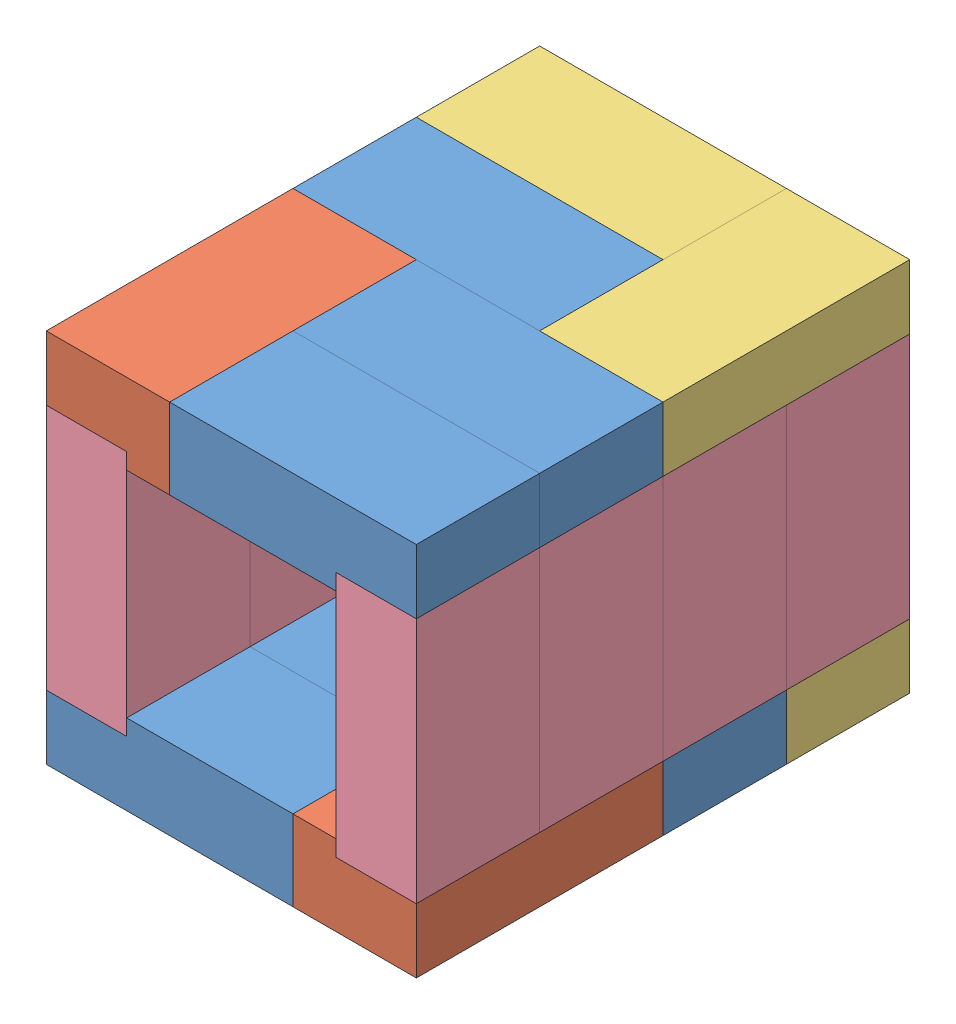
SolidWorks assembly Assem1, configuration Default. Lengths in mm.
Overall size (353.06 350 465.32).
27 component instances, 5 part files, 11 mates.
Components (placement in the parent):
- Heat Treat Asm Top-Bot Alt Long-1: Heat Treat Asm Top-Bot Alt Long [Default] at (93.1186 153.6522 453.2582) size (345 75 460)
  - Brick-Sharp-BackCut-1: Brick-Sharp-BackCut [Default] at (102.0414 124.8114 164.7515) size (230 75 115)
  - Brick-Sharp-SideCut-1: Brick-Sharp-SideCut [Default] at (274.5414 124.8114 107.2515) x (0 0 1) z (-1 0 0) size (230 75 115)
  - Brick-Sharp-BackCut-2: Brick-Sharp-BackCut [Default] at (102.0414 124.8114 49.7515) size (230 75 115)
  - Brick-Sharp-BackCut-3: Brick-Sharp-BackCut [Default] at (217.0414 124.8114 -65.2485) x (-1 0 0) z (0 0 -1) size (230 75 115)
  - Brick-Sharp-BackLeftCut-2: Brick-Sharp-BackLeftCut [Default] at (217.0414 124.8114 -180.2485) x (-1 0 0) z (0 0 -1) size (230 75 115)
  - Brick-Sharp-BackLeftCut-3: Brick-Sharp-BackLeftCut [Default] at (44.5414 124.8114 -122.7485) x (0 0 1) z (-1 0 0) size (230 75 115)
- Heat Treat Asm Top-Bot Alt Long-2: Heat Treat Asm Top-Bot Alt Long [Default] at (412.2014 678.275 453.2582) x (-1 0 0) z (0 0 1) size (345 75 460)
  - Brick-Sharp-BackCut-1: Brick-Sharp-BackCut [Default] at (102.0414 124.8114 164.7515) size (230 75 115)
  - Brick-Sharp-SideCut-1: Brick-Sharp-SideCut [Default] at (274.5414 124.8114 107.2515) x (0 0 1) z (-1 0 0) size (230 75 115)
  - Brick-Sharp-BackCut-2: Brick-Sharp-BackCut [Default] at (102.0414 124.8114 49.7515) size (230 75 115)
  - Brick-Sharp-BackCut-3: Brick-Sharp-BackCut [Default] at (217.0414 124.8114 -65.2485) x (-1 0 0) z (0 0 -1) size (230 75 115)
  - Brick-Sharp-BackLeftCut-2: Brick-Sharp-BackLeftCut [Default] at (217.0414 124.8114 -180.2485) x (-1 0 0) z (0 0 -1) size (230 75 115)
  - Brick-Sharp-BackLeftCut-3: Brick-Sharp-BackLeftCut [Default] at (44.5414 124.8114 -122.7485) x (0 0 1) z (-1 0 0) size (230 75 115)
- Heat Treat Asm Back-1: Heat Treat Asm Back [Default] at (559.1645 290.8305 184.2616) x (-0.008726 0.008727 0.999924) z (-0.999962 0 -0.008727) size (462.63 234.01 79.01)
  - Brick-Sharp-1: Brick-Sharp [Default] at (91.3299 124.3408 170.7235) x (-0.008727 -0.999962 0) z (-0.999924 0.008726 0.008727) size (230 75 115)
  - Brick-Sharp-2: Brick-Sharp [Default] at (206.3211 123.3373 169.7199) x (0.008727 0.999962 0) z (-0.999924 0.008726 0.008727) size (230 75 115)
  - Brick-Sharp-3: Brick-Sharp [Default] at (436.3036 121.3303 167.7128) x (-0.008727 -0.999962 0) z (0.999924 -0.008726 -0.008727) size (230 75 115)
  - Brick-Sharp-4: Brick-Sharp [Default] at (321.3124 122.3338 168.7164) x (-0.008727 -0.999962 0) z (0.999924 -0.008726 -0.008727) size (230 75 115)
- Heat Treat Asm Back-2: Heat Treat Asm Back [Default] at (-53.8445 290.8305 706.7578) x (0.008726 0.008727 -0.999924) z (0.999962 0 0.008727) size (462.63 234.01 79.01)
  - Brick-Sharp-1: Brick-Sharp [Default] at (91.3299 124.3408 170.7235) x (-0.008727 -0.999962 0) z (-0.999924 0.008726 0.008727) size (230 75 115)
  - Brick-Sharp-2: Brick-Sharp [Default] at (206.3211 123.3373 169.7199) x (0.008727 0.999962 0) z (-0.999924 0.008726 0.008727) size (230 75 115)
  - Brick-Sharp-3: Brick-Sharp [Default] at (436.3036 121.3303 167.7128) x (-0.008727 -0.999962 0) z (0.999924 -0.008726 -0.008727) size (230 75 115)
  - Brick-Sharp-4: Brick-Sharp [Default] at (321.3124 122.3338 168.7164) x (-0.008727 -0.999962 0) z (0.999924 -0.008726 -0.008727) size (230 75 115)
- Heat Treat Asm Back Alt-1: Heat Treat Asm Back Alt [Default] at (386.4278 496.0717 124.4337) x (0 -1 0) z (-1 0 0) size (230 75 195)
  - Brick-Sharp-1: Brick-Sharp [Default] at (80.1081 128.5759 173.7678) size (230 75 115)
  - Brick-Sharp-Trimmed-1: Brick-Sharp-Trimmed [Default] at (80.1081 128.5759 58.7678) size (230 75 80)
Mates (geometry in assembly coordinates):
- Coincident1: coincident anti-aligned: line of Heat Treat Asm Top-Bot Alt Long-1/Brick-Sharp-SideCut-1 through (350.16 300.9636 675.5097) axis (1 0 0); line of Heat Treat Asm Back-1/Brick-Sharp-3 through (425.16 300.9636 675.5097) axis (-1 0 0)
- Coincident2: coincident anti-aligned: line of Heat Treat Asm Top-Bot Alt Long-1/Brick-Sharp-BackLeftCut-2 through (425.16 300.9636 330.5097) axis (0 0 -1); line of Heat Treat Asm Back-1/Brick-Sharp-1 through (425.16 300.9636 215.5097) axis (0 0 1)
- Coincident4: coincident: plane of Heat Treat Asm Top-Bot Alt Long-1/Brick-Sharp-BackCut-1 through (195.16 300.9636 618.0097) normal (0 1 0); plane of Heat Treat Asm Back-2/Brick-Sharp-1 through (155.16 300.9636 560.5097) normal (0 -1 0)
- Coincident5: coincident: line of Heat Treat Asm Top-Bot Alt Long-1/Brick-Sharp-BackCut-1 through (80.16 300.9636 675.5097) axis (1 0 0); line of Heat Treat Asm Back-2/Brick-Sharp-1 through (155.16 300.9636 675.5097) axis (-1 0 0)
- Coincident6: coincident anti-aligned: line of Heat Treat Asm Top-Bot Alt Long-1/Brick-Sharp-BackCut-1 through (80.16 300.9636 560.5097) axis (0 0 1); line of Heat Treat Asm Back-2/Brick-Sharp-1 through (80.16 300.9636 675.5097) axis (0 0 -1)
- Coincident7: coincident: plane of Heat Treat Asm Top-Bot Alt Long-1/Brick-Sharp-BackLeftCut-3 through (137.66 300.9636 330.5097) normal (0 1 0); plane of Heat Treat Asm Back Alt-1/Brick-Sharp-1 through (270.16 300.9636 290.5097) normal (0 -1 0)
- Coincident8: coincident: line of Heat Treat Asm Top-Bot Alt Long-1/Brick-Sharp-BackLeftCut-2 through (425.16 300.9636 215.5097) axis (-1 0 0); line of Heat Treat Asm Back Alt-1/Brick-Sharp-Trimmed-1 through (270.16 300.9636 215.5097) axis (1 0 0)
- Coincident9: coincident anti-aligned: plane of Heat Treat Asm Back-1/Brick-Sharp-1 through (350.16 415.9636 273.0097) normal (-1 0 0); plane of Heat Treat Asm Back Alt-1/Brick-Sharp-Trimmed-1 through (350.16 415.9636 253.0097) normal (1 0 0)
- Coincident10: coincident: plane of Heat Treat Asm Top-Bot Alt Long-2/Brick-Sharp-SideCut-1 through (137.66 530.9636 560.5097) normal (0 -1 0); plane of Heat Treat Asm Back-2/Brick-Sharp-1 through (155.16 530.9636 560.5097) normal (0 1 0)
- Coincident11: coincident: line of Heat Treat Asm Top-Bot Alt Long-2/Brick-Sharp-BackLeftCut-3 through (310.16 530.9636 215.5097) axis (1 0 0); line of Heat Treat Asm Back-1/Brick-Sharp-1 through (350.16 530.9636 215.5097) axis (1 0 0)
- Coincident12: coincident aligned: line of Heat Treat Asm Top-Bot Alt Long-2/Brick-Sharp-BackCut-3 through (80.16 530.9636 445.5097) axis (0 0 -1); line of Heat Treat Asm Back-2/Brick-Sharp-4 through (80.16 530.9636 445.5097) axis (0 0 -1)
